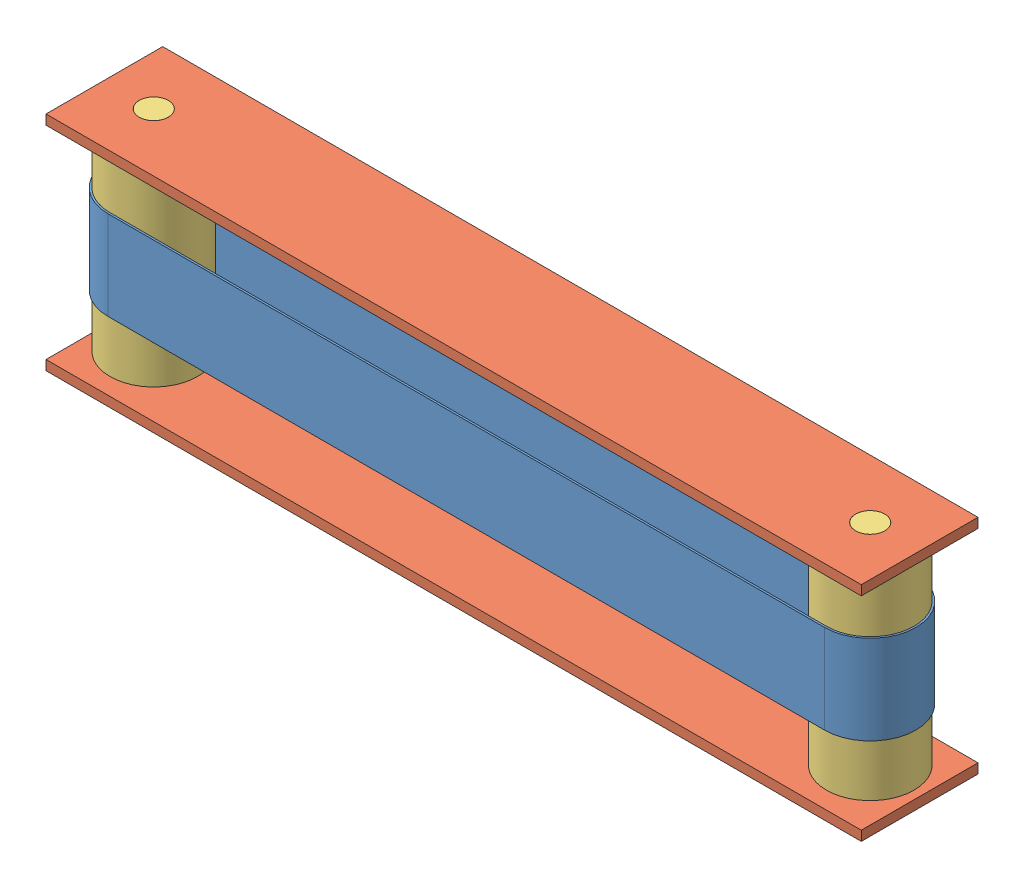
SolidWorks assembly Conveyor Small, configuration Default. Lengths in mm.
Overall size (419.1 114.3 60).
5 component instances, 3 part files, 10 mates.
Components (placement in the parent):
- Conveyor Belt_16_5-1: Conveyor Belt_16_5 [Default] at (-94.8728 225.7989 331.7755) size (415.3 45.72 47)
- Conveyor Stand_16_5-1: Conveyor Stand_16_5 [Default] at (-120.2728 301.4909 361.7755) size (419.1 5 60)
- Conveyor Stand_16_5-2: Conveyor Stand_16_5 [Default] at (-120.2728 192.1909 361.7755) size (419.1 5 60)
- Roller-1: Roller [Default] at (-94.8728 249.3409 331.7755) size (45 114.3 45)
- Roller-2: Roller [Default] at (273.4272 249.3409 331.7755) size (45 114.3 45)
Mates (geometry in assembly coordinates):
- Concentric1: concentric aligned: cylinder of Conveyor Stand_16_5-1 through (273.4272 276.5189 331.7755) axis (0 -1 0) radius 7.5; cylinder of Roller-2 through (273.4272 276.5189 331.7755) axis (0 -1 0) radius 7.5
- Coincident1: coincident aligned: plane of Conveyor Stand_16_5-1 through (-120.2728 276.5189 361.7755) normal (0 1 0); plane of Roller-2 through (273.4272 276.5189 331.7755) normal (0 1 0)
- Concentric2: concentric aligned: cylinder of Conveyor Stand_16_5-1 through (-94.8728 276.5189 331.7755) axis (0 -1 0) radius 7.5; cylinder of Roller-1 through (-94.8728 276.5189 331.7755) axis (0 -1 0) radius 7.5
- Coincident2: coincident aligned: plane of Conveyor Stand_16_5-1 through (-120.2728 276.5189 361.7755) normal (0 1 0); plane of Roller-1 through (-94.8728 276.5189 331.7755) normal (0 1 0)
- Distance1: distance = 29.972 mm anti-aligned: plane of Conveyor Belt_16_5-1 through (-94.8728 271.5189 331.7755) normal (0 1 0); plane of Conveyor Stand_16_5-1 through (-120.2728 301.4909 361.7755) normal (0 -1 0)
- Concentric3: concentric aligned: cylinder of Conveyor Belt_16_5-1 through (273.4272 271.5189 331.7755) axis (0 -1 0) radius 22.5; cylinder of Roller-2 through (273.4272 270.1689 331.7755) axis (0 -1 0) radius 22.5
- Concentric4: concentric aligned: cylinder of Conveyor Stand_16_5-2 through (273.4272 167.2189 331.7755) axis (0 -1 0) radius 7.5; cylinder of Roller-2 through (273.4272 276.5189 331.7755) axis (0 -1 0) radius 7.5
- Coincident4: coincident aligned: plane of Conveyor Stand_16_5-2 through (-120.2728 162.2189 361.7755) normal (0 -1 0); plane of Roller-2 through (273.4272 162.2189 331.7755) normal (0 -1 0)
- Coincident5: coincident aligned: plane of Conveyor Stand_16_5-1 through (-120.2728 276.5189 301.7755) normal (0 0 -1); plane of Conveyor Stand_16_5-2 through (-120.2728 167.2189 301.7755) normal (0 0 -1)
- Coincident6: coincident anti-aligned: circle of Conveyor Stand_16_5-2; cylinder of Roller-1 through (-94.8728 276.5189 331.7755) axis (0 -1 0) radius 7.5
